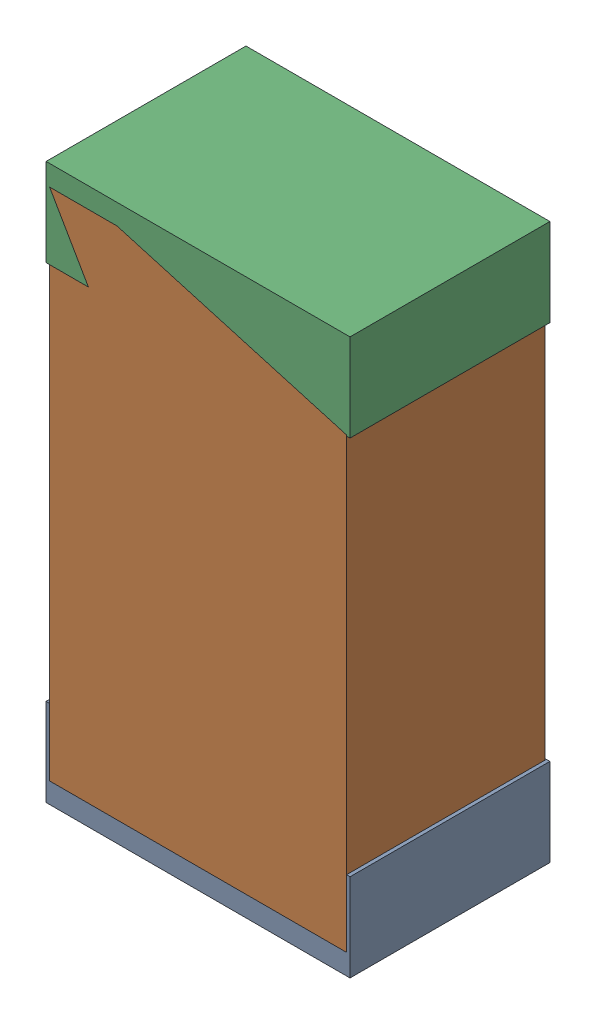
SolidWorks assembly R15, configuration Default. Lengths in mm.
Overall size (1.3 2.38 0.85).
6 component instances, 2 part files, 0 mates.
Components (placement in the parent):
- 402662288-1: 402662288 [Default] at (9.9822 65.8274 -1.9574) size (1.3 0.38 0.85)
  - Extruded_16-1: Extruded_16 [Default] at origin size (1.3 0.38 0.85)
- 402662416-1: 402662416 [Default] at (9.9822 66.8274 -1.9524) size (1.27 2.2 0.85)
  - Extruded_17-1: Extruded_17 [Default] at origin size (1.27 2.2 0.85)
- 402662288-2: 402662288 [Default] at (9.9822 67.8274 -1.9574) size (1.3 0.38 0.85)
  - Extruded_16-1: Extruded_16 [Default] at origin size (1.3 0.38 0.85)
